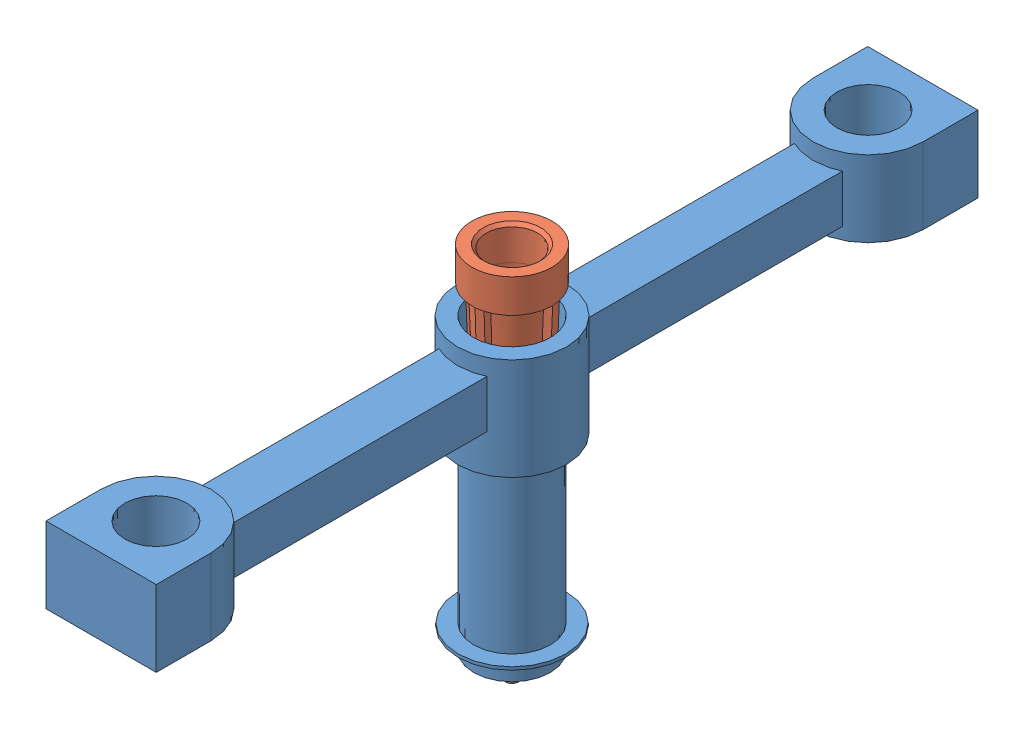
SolidWorks assembly New Mount Needle holder Assembly r1, configuration Default. Lengths in mm.
Overall size (9.2 31.44 68.58).
3 component instances, 3 part files, 2 mates.
Components (placement in the parent):
- New Mount Needle holder standard r1-1: New Mount Needle holder standard r1 [Default] at origin size (24.28 22.21 68.58) (hidden)
- New Mount Needle holder conductive r1-1: New Mount Needle holder conductive r1 [Default] at origin size (9.2 24.22 68.58)
- Qosina 11077-1: Qosina 11077 [Default] at (12.065 -19.86 -34.29) x (0.149921 0 0.988698) z (0 1 0) size (6.81 6.81 31.44)
Mates (geometry in assembly coordinates):
- Concentric2: concentric aligned: circle of Qosina 11077-1; circle of New Mount Needle holder conductive r1-1
- Distance2: distance = 2 mm aligned: plane of Qosina 11077-1 through (12.065 -19.86 -34.29) normal (0 -1 0); plane of New Mount Needle holder conductive r1-1 through (12.065 -17.86 -34.29) normal (0 -1 0)
